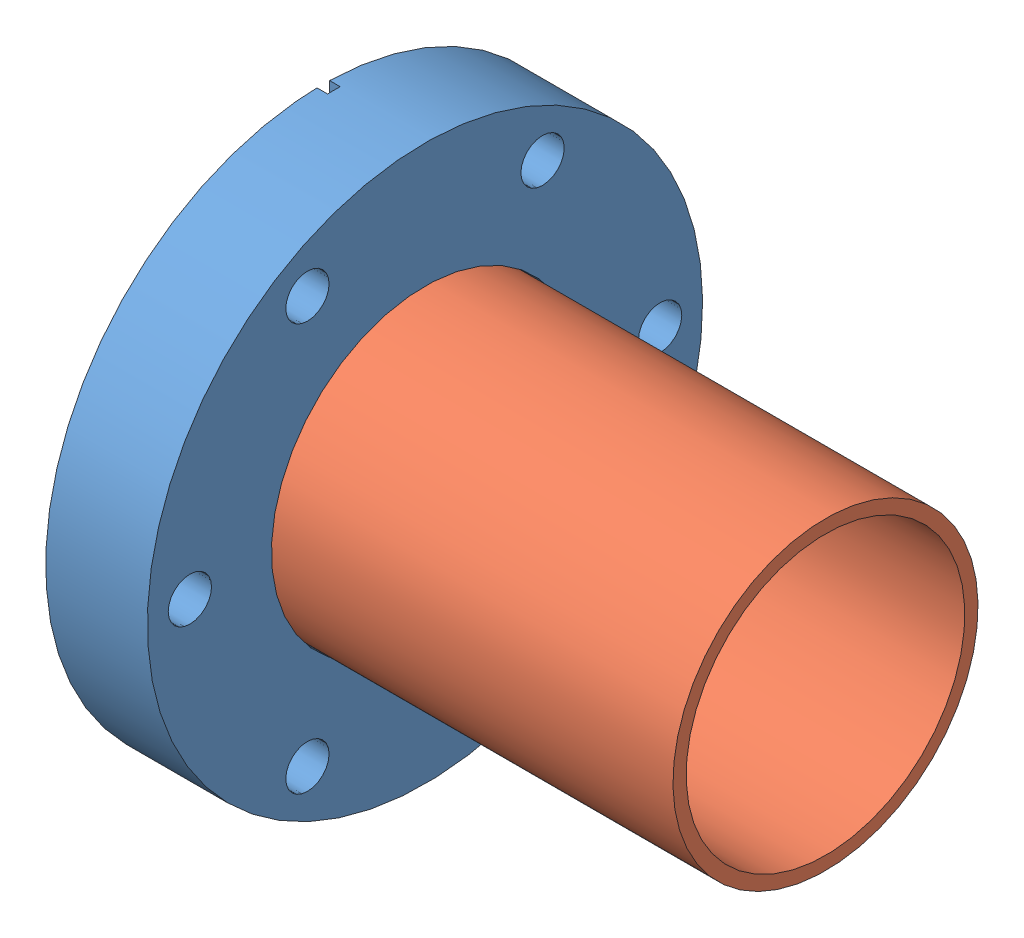
SolidWorks assembly 401023, configuration Default. Lengths in mm.
Overall size (62.71 94.72 94.72).
2 component instances, 2 part files, 3 mates.
Components (placement in the parent):
- 130014-1: 130014 [Default] at (5.2875 64.9268 0) x (1 0 0) z (0 0.5 0.866025) size (12.7 69.34 69.34)
- 940102-1: 940102 [Default] at (68.0001 64.9268 0) x (0 0.5 0.866025) z (-1 0 0) size (38.1 38.1 57.4)
Mates (geometry in assembly coordinates):
- Coincident1: coincident anti-aligned: plane of 130014-1 through (10.5961 81.5345 -9.5885) normal (1 0 0); plane of 940102-1 through (10.5961 64.9268 0) normal (-1 0 0)
- Concentric1: concentric anti-aligned: cylinder of 130014-1 through (5.2875 64.9268 0) axis (-1 0 0) radius 19.177; cylinder of 940102-1 through (10.5961 64.9268 0) axis (1 0 0) radius 19.05
- Coincident2: coincident aligned: plane of 130014-1 through (5.2875 64.9268 0) normal (0 0 1)
